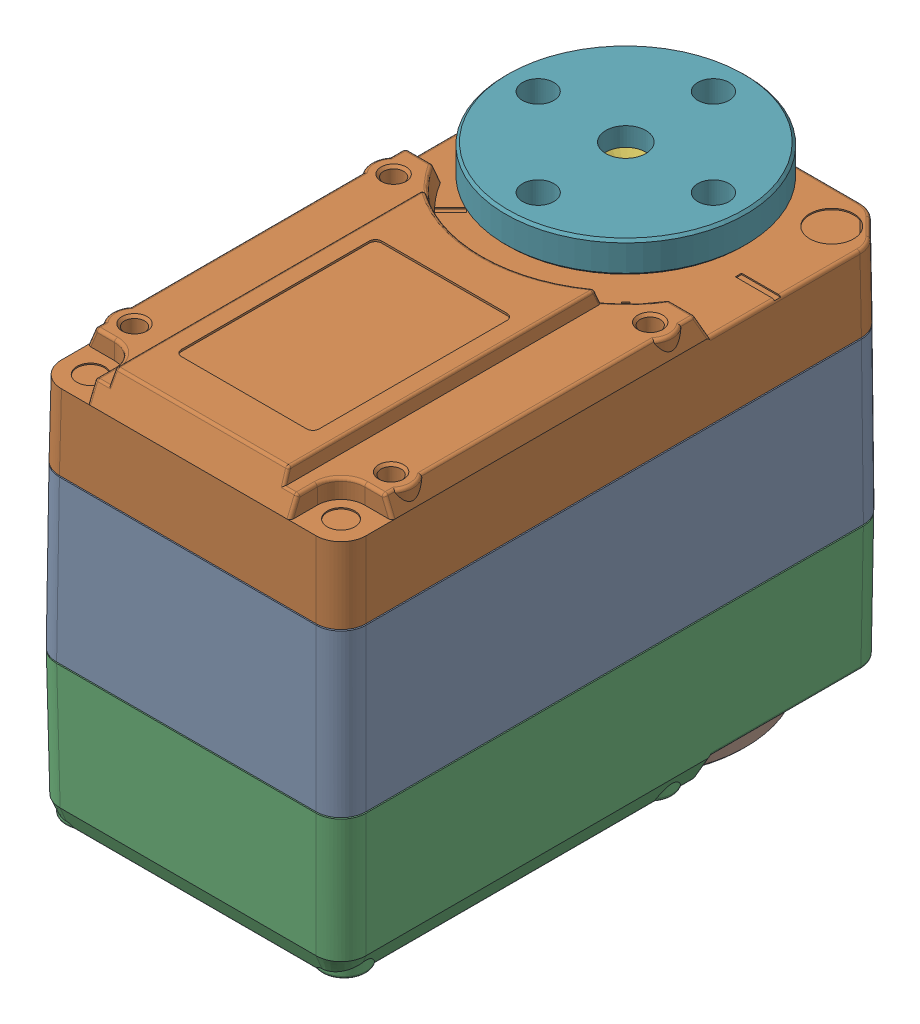
SolidWorks assembly ST3215_3, configuration Default. Lengths in mm.
Overall size (24.72 37.8 45.22).
8 component instances, 8 part files, 0 mates.
Components (placement in the parent):
- ZK_122-1: ZK_122 [Default] at (-120.2741 35.6502 27.4858) x (0 0 1) z (-1 0 0) size (45.22 13.9 24.72)
- SG-ZIJI_15-1: SG-ZIJI_15 [Default] at (-120.2741 35.6502 27.4858) x (0 0 1) z (-1 0 0) size (45 9.77 24.5)
- XG-ZIJI_16-1: XG-ZIJI_16 [Default] at (-120.2741 35.6502 27.4858) x (0 0 1) z (-1 0 0) size (45.22 14.1 24.72)
- MOTOR-1723_3-1: MOTOR-1723_3 [Default] at (-119.0241 12.8002 27.4858) size (17.05 30.5 17.05)
- PCB-CHAZUO_92-1: PCB-CHAZUO_92 [Default] at (-120.2741 35.6502 27.4858) x (0 0 1) z (-1 0 0) size (28.8 7.2 21.1)
- GE_27-1: GE_27 [Default] at (-120.2741 29.6502 1.9858) x (0 0 1) z (0 -1 0) size (17.6 17.59 18.3)
- 金属舵盘（驱动）-1: 金属舵盘（驱动） [Default] at (-120.2741 18.2502 -8.0142) x (0 0 1) z (-1 0 0) size (19.2 4.5 19.2)
- 金属舵盘（从动）-1: 金属舵盘（从动） [Default] at (-120.2741 -13.7998 11.9858) x (0 0 -1) z (-1 0 0) size (19.2 3.35 19.2)
